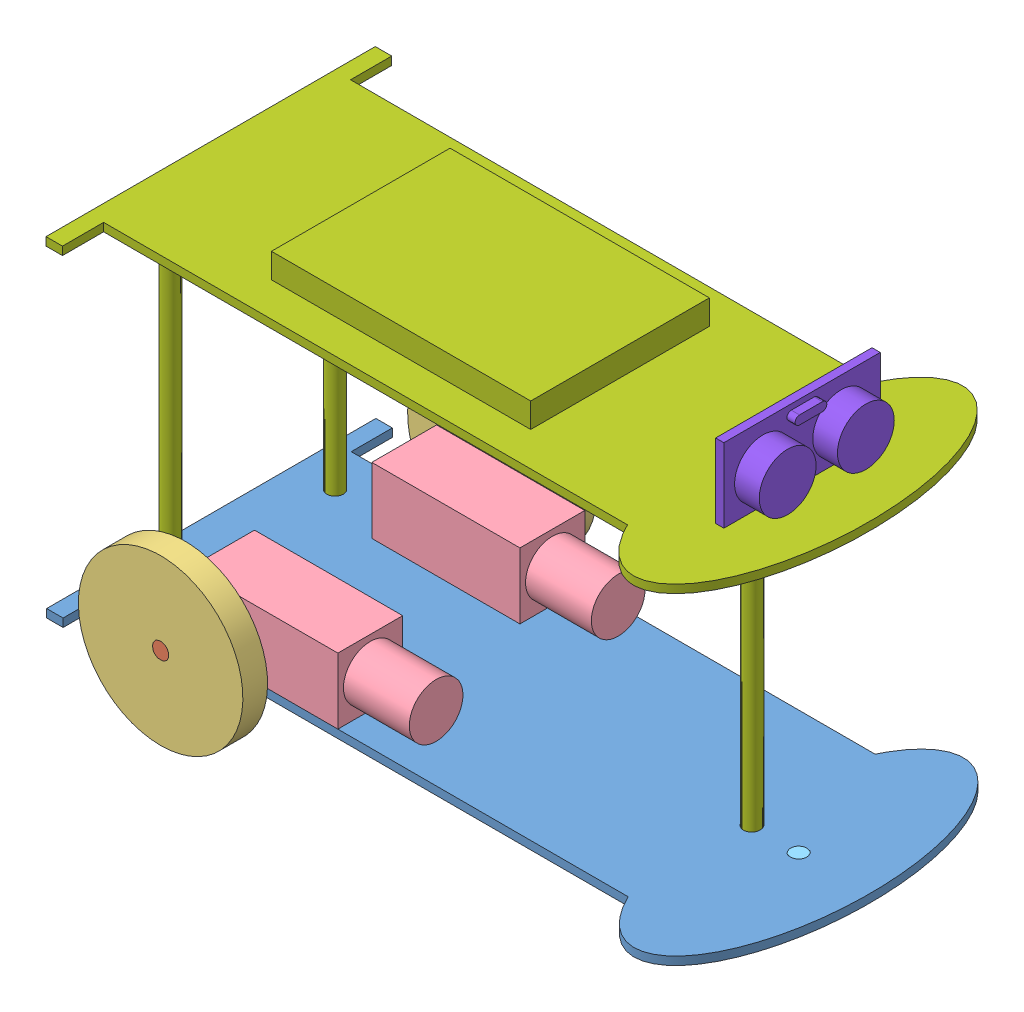
SolidWorks assembly cad work atulya, configuration Default. Lengths in mm.
Overall size (203.62 139.86 109.22).
11 component instances, 8 part files, 18 mates.
Components (placement in the parent):
- lower-1: lower [Default] at (66.9622 73.9085 162.597) size (203.2 2.54 101.61)
- wheel axle-1: wheel axle [Default] at (25.7367 86.3106 229.1195) x (1 0 0) z (0 1 0) size (5.08 35.56 5.08)
- wheel axle-2: wheel axle [Default] at (25.2028 89.4266 119.8995) x (0.94688 0.321587 0) z (0.321587 -0.94688 0) size (5.08 35.56 5.08)
- back wheels-1: back wheels [Default] at (17.8508 86.6085 229.1195) x (1 0 0) z (0 1 0) size (50.75 7.62 50.75)
- motor-3: motor [Default] at (27.7603 76.4485 137.6947) x (-1 0 0) z (0 0 -1) size (66.04 20.32 20)
- motor-4: motor [Default] at (27.7795 96.7685 211.3243) x (-1 0 0) z (0 0 1) size (66.04 20.32 20)
- back wheels-3: back wheels [Default] at (17.8316 86.6085 119.8995) x (0.993466 -0.11413 0) z (-0.11413 -0.993466 0) size (50.75 7.62 50.75)
- castor body-2: castor body [Default] at (155.0313 73.6545 187.207) x (0 0 -1) z (1 0 0) size (25.4 12.7 10.16)
- wheel for castor-3: wheel for castor [Default] at (148.8092 76.4084 171.967) x (0 1 0) z (1 0 0) size (10.16 25.4 10.16)
- upper-4: upper [Default] at (66.9622 175.5085 186.198) x (1 0 0) z (0 0 -1) size (203.2 109.22 101.61)
- ultrasonic sensor-7: ultrasonic sensor [Default] at (158.4217 193.2084 167.9922) x (0 0 -1) z (0 -1 0) size (48.26 10.16 25.4)
Mates (geometry in assembly coordinates):
- Coincident10: coincident anti-aligned: line of lower-1 through (-16.0585 76.4485 212.6095) axis (1 0 0); line of motor-4 through (56.0282 76.4485 212.6095) axis (-1 0 0)
- Coincident13: coincident anti-aligned: line of lower-1 through (-16.0585 76.4485 136.4095) axis (1 0 0); line of motor-3 through (56.009 76.4485 136.4095) axis (-1 0 0)
- Coincident14: coincident anti-aligned: plane of lower-1 through (66.9622 76.4485 162.597) normal (0 1 0); plane of motor-4 through (27.7795 76.4485 211.3243) normal (0 -1 0)
- Coincident15: coincident anti-aligned: plane of lower-1 through (66.9622 76.4485 162.597) normal (0 1 0); plane of motor-3 through (27.7603 76.4485 137.6947) normal (0 -1 0)
- Coincident18: coincident anti-aligned: circle of wheel axle-1; circle of motor-4
- Coincident19: coincident anti-aligned: circle of wheel axle-2; circle of motor-3
- Concentric9: concentric anti-aligned: cylinder of wheel axle-1 through (17.8508 86.6085 193.5595) axis (0 0 1) radius 2.54; cylinder of back wheels-1 through (17.8508 86.6085 229.1195) axis (0 0 -1) radius 2.4923
- Concentric10: concentric aligned: circle of wheel axle-1; circle of back wheels-1
- Coincident21: coincident anti-aligned: plane of wheel axle-1 through (17.8508 86.6085 229.1195) normal (0 0 1); circle of back wheels-1
- Concentric14: concentric anti-aligned: axis of wheel axle-2 through (17.8316 86.6085 155.4595) axis (0 0 -1); cylinder of back wheels-3 through (17.8316 86.6085 119.8995) axis (0 0 1) radius 2.4923
- Concentric15: concentric aligned: circle of wheel axle-2; circle of back wheels-3
- Coincident22: coincident anti-aligned: circle of wheel axle-2; plane of back wheels-3 through (17.8316 86.6085 119.8995) normal (0 0 -1)
- Coincident33: coincident aligned: circle of castor body-2; circle of wheel for castor-3
- Concentric20: concentric aligned: circle of lower-1; circle of castor body-2
- Coincident41: coincident anti-aligned: circle of lower-1; circle of upper-4
- Coincident42: coincident anti-aligned: circle of lower-1; circle of upper-4
- Coincident50: coincident: line of ultrasonic sensor-7 through (160.9617 172.9685 198.4366) axis (-1 0 0); line of upper-4 through (158.4217 172.9685 198.4366) axis (1 0 0)
- Coincident51: coincident anti-aligned: line of upper-4 through (160.9617 172.9685 150.1394) axis (0 0 1); line of ultrasonic sensor-7 through (160.9617 172.9685 198.4366) axis (0 0 -1)
